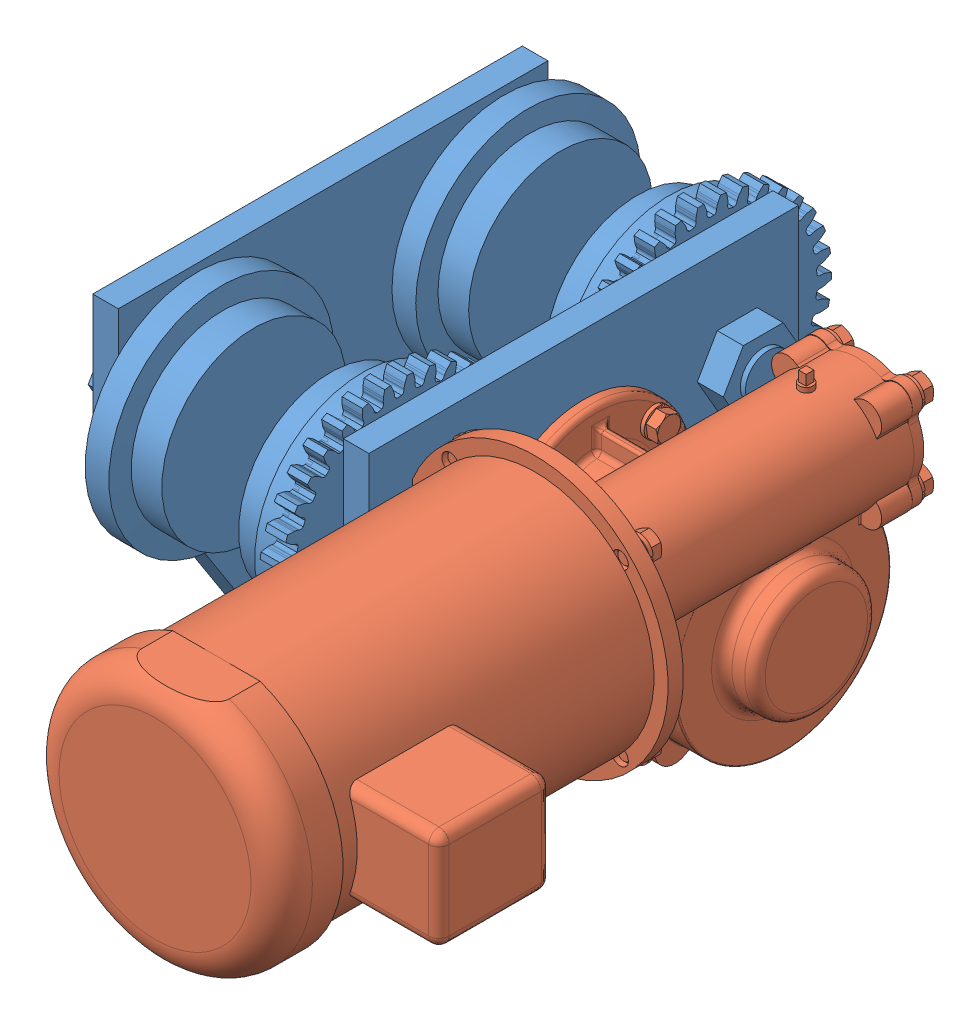
SolidWorks assembly M2632C-LH, configuration Default. Lengths in mm.
Overall size (418.5 387.47 540.72).
2 component instances, 2 part files, 3 mates.
Components (placement in the parent):
- Copy of M2632C-TROLLEY-SECTION^M2632C-LH-1: Copy of M2632C-TROLLEY-SECTION^M2632C-LH [3.25 PAT TRACK] at origin size (210.26 349.64 342.81) (virtual)
- Copy of SDT GEAR REDUCER LH^M2632C-LH-1: Copy of SDT GEAR REDUCER LH^M2632C-LH [Default] at (188.9125 104.394 0) x (-1 0 0) z (0 0 -1) size (229.23 225.42 451.54) (virtual)
Mates (geometry in assembly coordinates):
- Coincident1: coincident aligned: plane of Copy of M2632C-TROLLEY-SECTION^M2632C-LH-1 through (0 104.394 0) normal (0 1 0); plane of Copy of SDT GEAR REDUCER LH^M2632C-LH-1
- Coincident2: coincident anti-aligned: plane of Copy of M2632C-TROLLEY-SECTION^M2632C-LH-1 through (0 0 0) normal (0 0 1); plane of Copy of SDT GEAR REDUCER LH^M2632C-LH-1 through (188.9125 104.394 0) normal (0 0 -1)
- Distance1: distance = 14.2875 mm aligned: plane of Copy of SDT GEAR REDUCER LH^M2632C-LH-1 through (84.1375 104.394 0) normal (-1 0 0); plane of Copy of M2632C-TROLLEY-SECTION^M2632C-LH-1 through (69.85 203.2 -133.35) normal (-1 0 0)
